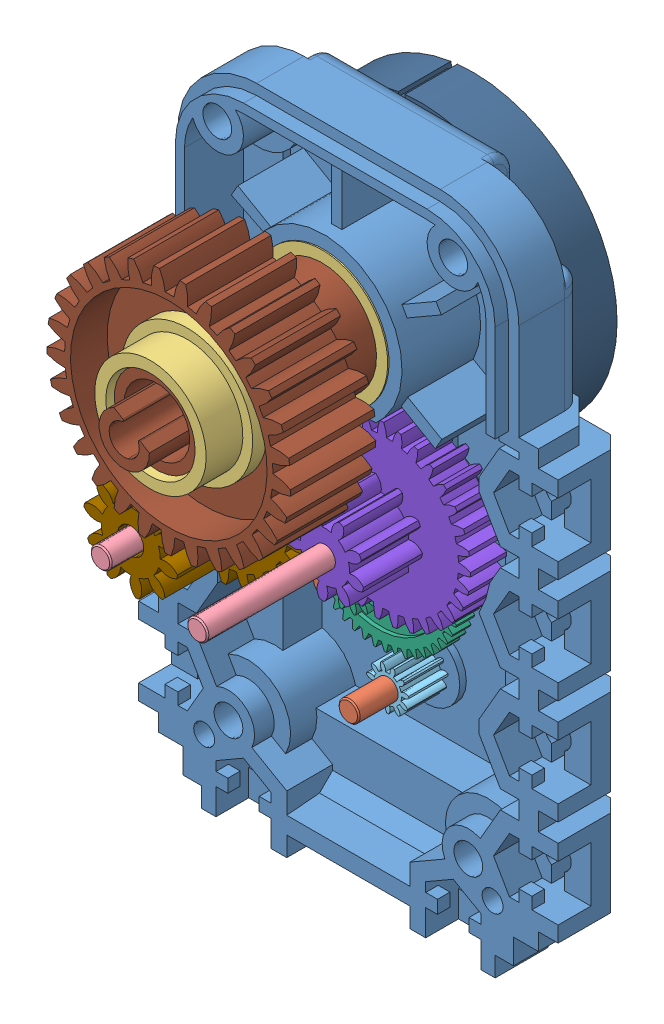
SolidWorks assembly AX-12A_ensemble_transmission, configuration Défaut. Lengths in mm.
Overall size (40.29 55.31 27.3).
16 component instances, 11 part files, 12 mates.
Components (placement in the parent):
- AX-12A_carter_transmission-1: AX-12A_carter_transmission [Défaut] at (48.5325 17.7651 -0.8809) x (0.99653 0.083229 0) z (-0.083229 0.99653 0) size (36.05 23.44 52.49)
  - couvercle AX-12-1: couvercle AX-12 [Défaut] at (-30.6939 -8.8809 23.3706) x (0.99653 0 -0.083229) z (0.083229 0 0.99653) size (32 9.94 50)
  - axe 7mm-1: axe 7mm [Défaut] at (-34.4542 -1.6809 4.2855) x (1 0 0) z (0 -1 0) size (1.6 1.6 7)
  - Bague 6ème Pignon-1: Bague 6ème Pignon [Défaut] at (-30.6939 -20.0809 23.3706) x (0 -1 0) z (0 0 1) size (3.9 10 10)
  - Bague 6ème Pignon-2: Bague 6ème Pignon [Défaut] at (-30.6939 -10.8809 23.3706) x (0 1 0) z (0 0 1) size (3.9 10 10)
  - axe 20mm-1: axe 20mm [Défaut] at (-36.1363 -3.2809 12.3592) x (1 0 0) z (0 -1 0) size (1.6 1.6 20)
  - axe 20mm-2: axe 20mm [Défaut] at (-27.8058 -4.2809 11.5894) x (1 0 0) z (0 -1 0) size (1.6 1.6 20)
  - axe 7mm-2: axe 7mm [Défaut] at (-32.8995 -8.8809 -3.0374) x (0.64246 0 -0.766319) z (0 1 0) size (1.6 1.6 7)
- Pigon moteur-1: Pigon moteur [Metric - Spur gear 0.25M 11T 14.5PA 3FW ---S11N75H50L0.8N] at (16 12 2) x (0 0 1) z (-1 0 0) size (3 3.2 3.23)
- 2ème Pignon-1: 2ème Pignon [Défaut] at (12.7655 8.6735 6.7638) x (0 0 1) z (-0.994789 0.101956 0) size (3.9 12.48 12.48)
- 3ème Pignon-1: 3ème Pignon [Défaut] at (12.0451 11.6272 -28.6687) x (0 0 1) z (-0.999362 -0.035722 0) size (4.9 11.97 12)
- 4ème Pignon-1: 4ème Pignon [Défaut] at (21.6889 12.6309 20.349) x (0 0 -1) z (0.991985 0.126358 0) size (7.25 13.18 13.2)
- 5ème Pignon-1: 5ème Pignon [Défaut] at (6.518 -1.9438 38.8644) x (0 0 1) z (-0.985619 0.16898 0) size (10.9 12.49 12.47)
- AX-12A_arbre_sortie-1: AX-12A_arbre_sortie [Défaut] at (44.8926 12.936 -0.8809) x (0.997294 -0.07352 0) z (0.07352 0.997294 0) size (26 27.3 26)
  - 9_ALL_COMPONENTS_1-1-1: 9_ALL_COMPONENTS_1-1 [Défaut] at (-30.6939 -9.3809 23.3706) x (0.97926 0 0.202606) z (-0.202606 0 0.97926) size (22 9.8 22)
  - 6ème Pignon-1: 6ème Pignon [Défaut] at (-27.767 -14.8019 29.0568) x (0 -1 0) z (0.889119 0 -0.457676) size (24.5 18.57 18.59)
Mates (geometry in assembly coordinates):
- Coïncidente1: coincident anti-aligned: plane of AX-12A_carter_transmission-1/couvercle AX-12-1 through (16 12 2) normal (0 0 1); plane of Pigon moteur-1 through (16 12 2) normal (0 0 -1)
- Coaxiale2: concentric aligned: cylinder of AX-12A_carter_transmission-1/axe 7mm-2 through (16 12 1) axis (0 0 1) radius 0.8; cylinder of Pigon moteur-1 through (16 12 -5) axis (0 0 1) radius 0.74
- Coïncidente2: coincident anti-aligned: plane of AX-12A_carter_transmission-1/couvercle AX-12-1 through (11.4491 21.5602 2.2) normal (0 0 1); plane of 2ème Pignon-1 through (13.8411 19.1682 2.2) normal (0 0 -1)
- Coaxiale3: concentric aligned: cylinder of AX-12A_carter_transmission-1/axe 7mm-1 through (13.8411 19.1682 7.8) axis (0 0 -1) radius 0.8; cylinder of 2ème Pignon-1 through (13.8411 19.1682 53.6001) axis (0 0 -1) radius 0.75
- Coïncidente3: coincident anti-aligned: plane of AX-12A_carter_transmission-1/couvercle AX-12-1 through (9.097 24.9277 5.3) normal (0 0 1); plane of 3ème Pignon-1 through (11.4929 27.0738 5.3) normal (0 0 -1)
- Coaxiale4: concentric anti-aligned: cylinder of AX-12A_carter_transmission-1/axe 20mm-1 through (11.4929 27.0738 22.4) axis (0 0 -1) radius 0.8; cylinder of 3ème Pignon-1 through (11.4929 27.0738 -0.8) axis (0 0 1) radius 0.95
- Coïncidente4: coincident anti-aligned: plane of AX-12A_carter_transmission-1/couvercle AX-12-1 through (17.9744 25.1179 6.4) normal (0 0 1); plane of 4ème Pignon-1 through (19.8586 27 6.4) normal (0 0 -1)
- Coaxiale5: concentric anti-aligned: cylinder of AX-12A_carter_transmission-1/axe 20mm-2 through (19.8586 27 23.4) axis (0 0 -1) radius 0.8; cylinder of 4ème Pignon-1 through (19.8586 27 9.15) axis (0 0 1) radius 0.8
- Distance1: distance = 16.2 mm aligned: plane of 5ème Pignon-1 through (11.4929 27.0738 20.1) normal (0 0 1); plane of AX-12A_carter_transmission-1/couvercle AX-12-1 through (4.7048 21.5436 3.9) normal (0 0 1)
- Coaxiale6: concentric aligned: cylinder of AX-12A_carter_transmission-1/axe 20mm-1 through (11.4929 27.0738 22.4) axis (0 0 -1) radius 0.8; cylinder of 5ème Pignon-1 through (11.4929 27.0738 63.1001) axis (0 0 -1) radius 1
- Coïncidente7: coincident anti-aligned: plane of AX-12A_carter_transmission-1/Bague 6ème Pignon-2 through (12.6118 38.217 10) normal (0 0 1); plane of AX-12A_arbre_sortie-1/6ème Pignon-1 through (16 38.5 10) normal (0 0 -1)
- Coaxiale7: concentric aligned: cylinder of AX-12A_carter_transmission-1/Bague 6ème Pignon-2 through (16 38.5 10) axis (0 0 1) radius 3.4; cylinder of AX-12A_arbre_sortie-1/6ème Pignon-1 through (16 38.5 6.3) axis (0 0 1) radius 3.35
